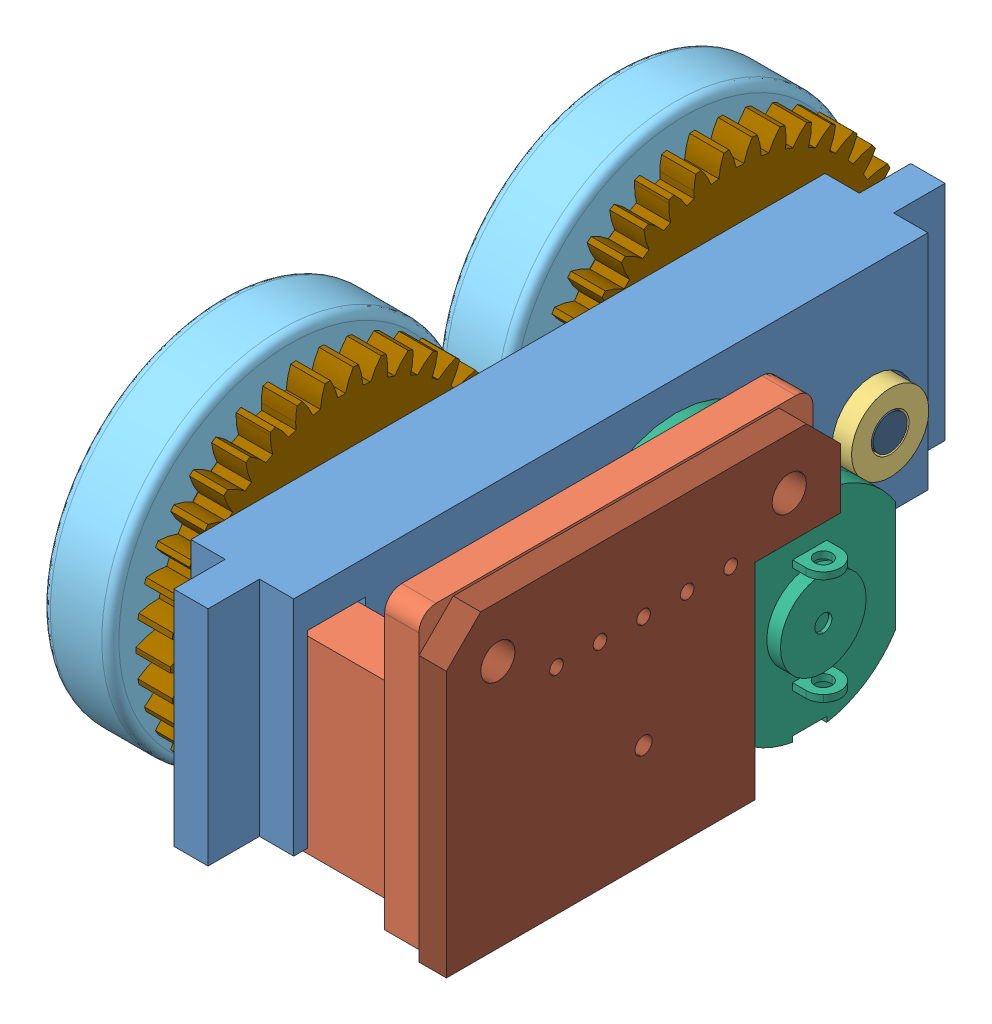
SolidWorks assembly Assem1, configuration Default. Lengths in mm.
Overall size (26.61 22.13 47.3).
19 component instances, 12 part files, 41 mates.
Components (placement in the parent):
- Cum Banh 1-1: Cum Banh 1 [Default] at (16.5178 20.2239 29.5226) x (0 0 -1) z (1 0 0) size (43 13 7.5)
- Ga encoder 1-1: Ga encoder 1 [Default] at (28.5178 22.8543 41.2226) x (0 0 -1) z (0 -1 0) size (23 12 17)
- Ga nam chamV3-1: Ga nam chamV3 [Default] at (21.0178 20.2239 18.0226) x (1 0 0) z (0 -0.059126 0.998251) size (2.5 4.5 4.5)
- Ga nam chamV3.1-1: Ga nam chamV3.1 [Default] at (20.5178 20.2239 41.0226) x (1 0 0) z (0 -0.620557 0.784161) size (7 7.5 7.5)
- Lop banh xe-1: Lop banh xe [Default] at (6.5178 20.2239 41.0226) size (4 21 21)
- N20 DC MOTOR Truc dai-1: N20 DC MOTOR Truc dai [Default] at (30.3178 20.1445 29.5225) x (0 1 0) z (0 0 1) size (12.48 22.6 10.65)
- Nam cham-1: Nam cham [Default] at (26.5178 20.2239 41.0226) x (0 -0.952578 -0.304296) z (1 0 0) size (4 4 2)
- Part4-1: Part4 [Default] at (12.5178 20.2239 41.0226) x (-1 0 0) z (0 0 -1) size (7 15 15)
- Spur gear 0.5M 38T-1: Spur gear 0.5M 38T [Default] at (12.5178 20.2239 41.0226) size (5 19.95 20)
- Truc 2x20-1: Truc 2x20 [Default] at (14.5178 20.2239 41.0226) x (0 0 -1) z (1 0 0) size (2 2 18)
- MT6701 Ver2-1: MT6701 Ver2 [Default] at (32.1278 20.2239 41.0226) x (0 0 -1) z (-1 0 0) size (23 17.5 3.61)
- Part4-2: Part4 [Default] at (12.5178 20.2239 18.0226) x (-1 0 0) z (0 0 -1) size (7 15 15)
- Truc 2x20-2: Truc 2x20 [Default] at (14.5178 20.2239 18.0226) x (0 0.989004 -0.147887) z (1 0 0) size (2 2 18)
- Lop banh xe-2: Lop banh xe [Default] at (6.5178 20.2239 18.0226) size (4 21 21)
- Spur gear 0.5M 38T-2: Spur gear 0.5M 38T [Default] at (12.5178 20.2239 18.0226) x (1 0 0) z (0 0.027407 0.999624) size (5 19.95 20)
- Vong bi 2x5x2.5-2: Vong bi 2x5x2.5 [Default] at (18.627 20.2239 41.0226) x (0 0 -1) z (1 0 0) size (5 5 3)
- Vong bi 2x5x2.5-3: Vong bi 2x5x2.5 [Default] at (21.627 20.2239 41.0226) x (0 0 -1) z (1 0 0) size (5 5 3)
- Vong bi 2x5x2.5-4: Vong bi 2x5x2.5 [Default] at (18.627 20.2239 18.0226) x (0 0 -1) z (1 0 0) size (5 5 3)
- Vong bi 2x5x2.5-6: Vong bi 2x5x2.5 [Default] at (21.627 20.2239 18.0226) x (0 0 -1) z (1 0 0) size (5 5 3)
Mates (geometry in assembly coordinates):
- Concentric1: concentric aligned: cylinder of Cum Banh 1-1 through (22.5178 20.2239 41.0226) axis (-1 0 0) radius 2.6; cylinder of Truc 2x20-1 through (22.3546 20.2239 41.0226) axis (-1 0 0) radius 1
- Concentric2: concentric aligned: cylinder of Cum Banh 1-1 through (22.5178 20.2239 41.0226) axis (-1 0 0) radius 2.6; cylinder of Lop banh xe-1 through (5.3546 20.2239 41.0226) axis (-1 0 0) radius 5.5
- Concentric3: concentric anti-aligned: cylinder of Cum Banh 1-1 through (22.5178 20.2239 41.0226) axis (-1 0 0) radius 2.6; cylinder of Part4-1 through (11.3546 20.2239 41.0226) axis (1 0 0) radius 5.1
- Concentric4: concentric anti-aligned: cylinder of Cum Banh 1-1 through (22.5178 20.2239 41.0226) axis (-1 0 0) radius 2.6; cylinder of Spur gear 0.5M 38T-1 through (8.3546 20.2239 41.0226) axis (1 0 0) radius 2.5
- Concentric5: concentric anti-aligned: cylinder of Cum Banh 1-1 through (22.5178 20.2239 41.0226) axis (-1 0 0) radius 2.6; cylinder of Vong bi 2x5x2.5-2 through (18.627 20.2239 41.0226) axis (1 0 0) radius 2.5
- Concentric6: concentric anti-aligned: cylinder of Cum Banh 1-1 through (22.5178 20.2239 41.0226) axis (-1 0 0) radius 2.6; cylinder of Vong bi 2x5x2.5-3 through (21.627 20.2239 41.0226) axis (1 0 0) radius 2.5
- Concentric7: concentric aligned: cylinder of Cum Banh 1-1 through (22.5178 20.2239 41.0226) axis (-1 0 0) radius 2.6; cylinder of Ga nam chamV3.1-1 through (19.3546 20.2239 41.0226) axis (-1 0 0) radius 3.75
- Concentric8: concentric aligned: cylinder of Cum Banh 1-1 through (22.5178 20.2239 41.0226) axis (-1 0 0) radius 2.6; cylinder of Nam cham-1 through (26.3546 20.2239 41.0226) axis (-1 0 0) radius 2
- Concentric9: concentric aligned: cylinder of Cum Banh 1-1 through (22.5178 20.2239 41.0226) axis (-1 0 0) radius 2.6; cylinder of MT6701 Ver2-1 through (32.3546 20.2239 41.0226) axis (-1 0 0) radius 0.5
- Concentric10: concentric aligned: cylinder of Cum Banh 1-1 through (22.5178 20.2239 18.0226) axis (-1 0 0) radius 2.6; cylinder of Ga nam chamV3-1 through (20.834 20.2239 18.0226) axis (-1 0 0) radius 2.25
- Concentric11: concentric anti-aligned: cylinder of Cum Banh 1-1 through (22.5178 20.2239 18.0226) axis (-1 0 0) radius 2.6; cylinder of Spur gear 0.5M 38T-2 through (8.3546 20.2239 18.0226) axis (1 0 0) radius 2.5
- Concentric12: concentric anti-aligned: cylinder of Cum Banh 1-1 through (22.5178 20.2239 18.0226) axis (-1 0 0) radius 2.6; cylinder of Part4-2 through (11.3546 20.2239 18.0226) axis (1 0 0) radius 5.1
- Concentric13: concentric aligned: cylinder of Cum Banh 1-1 through (22.5178 20.2239 18.0226) axis (-1 0 0) radius 2.6; cylinder of Lop banh xe-2 through (5.3546 20.2239 18.0226) axis (-1 0 0) radius 5.5
- Concentric14: concentric aligned: cylinder of Cum Banh 1-1 through (22.5178 20.2239 18.0226) axis (-1 0 0) radius 2.6; cylinder of Truc 2x20-2 through (23.5178 20.2239 18.0226) axis (-1 0 0) radius 1
- Concentric15: concentric aligned: cylinder of MT6701 Ver2-1 through (34.4646 28.7239 49.5226) axis (-1 0 0) radius 1; cylinder of Ga encoder 1-1 through (29.3546 28.7239 49.5226) axis (-1 0 0) radius 1
- Coincident1: coincident anti-aligned: plane of Part4-1 through (10.3546 20.2239 48.5226) normal (-1 0 0); plane of Lop banh xe-1 through (10.3546 30.7239 41.0226) normal (1 0 0)
- Coincident2: coincident anti-aligned: plane of Part4-1 through (11.3546 20.2239 43.5226) normal (1 0 0); plane of Spur gear 0.5M 38T-1 through (11.3546 20.2239 41.0226) normal (-1 0 0)
- Coincident3: coincident anti-aligned: plane of Spur gear 0.5M 38T-2 through (11.3546 20.2239 18.0226) normal (-1 0 0); plane of Part4-2 through (11.3546 20.2239 20.5226) normal (1 0 0)
- Coincident4: coincident anti-aligned: plane of Lop banh xe-2 through (10.3546 30.7239 18.0226) normal (1 0 0); plane of Part4-2 through (10.3546 20.2239 25.5226) normal (-1 0 0)
- Coincident5: coincident anti-aligned: plane of Vong bi 2x5x2.5-3 through (17.5178 22.7239 41.0226) normal (-1 0 0); plane of Vong bi 2x5x2.5-2 through (17.5178 22.2239 41.0226) normal (1 0 0)
- Coincident6: coincident anti-aligned: plane of Vong bi 2x5x2.5-4 through (17.5178 22.2239 18.0226) normal (1 0 0); plane of Vong bi 2x5x2.5-6 through (17.5178 22.7239 18.0226) normal (-1 0 0)
- Coincident7: coincident aligned: plane of Truc 2x20-1 through (4.3546 20.2239 41.0226) normal (-1 0 0); plane of Part4-1 through (4.3546 20.2239 42.1226) normal (-1 0 0)
- Coincident8: coincident aligned: plane of Truc 2x20-1 through (4.3546 20.2239 41.0226) normal (-1 0 0); plane of Truc 2x20-2 through (5.5178 20.2239 18.0226) normal (-1 0 0)
- Coincident9: coincident aligned: plane of Truc 2x20-1 through (4.3546 20.2239 41.0226) normal (-1 0 0); plane of Part4-2 through (4.3546 20.2239 19.1226) normal (-1 0 0)
- Coincident10: coincident anti-aligned: plane of Cum Banh 1-1 through (20.5178 20.2239 41.0226) normal (-1 0 0); plane of Vong bi 2x5x2.5-3 through (20.5178 22.2239 41.0226) normal (1 0 0)
- Coincident11: coincident anti-aligned: plane of Cum Banh 1-1 through (20.5178 20.2239 18.0226) normal (-1 0 0); plane of Vong bi 2x5x2.5-6 through (20.5178 22.2239 18.0226) normal (1 0 0)
- Concentric16: concentric anti-aligned: cylinder of N20 DC MOTOR Truc dai-1 through (14.2546 20.2239 29.5226) axis (1 0 0) radius 5.9205; cylinder of Cum Banh 1-1 through (22.5178 20.2239 29.5226) axis (-1 0 0) radius 6.25
- Parallel1: parallel aligned: plane of N20 DC MOTOR Truc dai-1 through (14.2546 16.8945 24.5225) normal (0 0 -1); plane of Cum Banh 1-1 through (22.5178 20.2239 34.6226) normal (0 0 -1)
- Concentric17: concentric aligned: cylinder of Vong bi 2x5x2.5-4 through (18.627 20.2239 18.0226) axis (1 0 0) radius 2.5; cylinder of Vong bi 2x5x2.5-6 through (21.627 20.2239 18.0226) axis (1 0 0) radius 2.5
- Concentric18: concentric anti-aligned: cylinder of Vong bi 2x5x2.5-4 through (18.627 20.2239 18.0226) axis (1 0 0) radius 2.5; cylinder of Cum Banh 1-1 through (22.5178 20.2239 18.0226) axis (-1 0 0) radius 2.6
- Coincident13: coincident anti-aligned: plane of Ga nam chamV3.1-1 through (24.3546 21.8706 42.3258) normal (1 0 0); plane of Nam cham-1 through (24.3546 20.2239 41.0226) normal (-1 0 0)
- Coincident14: coincident anti-aligned: plane of Truc 2x20-1 through (22.3546 20.2239 41.0226) normal (1 0 0); plane of Ga nam chamV3.1-1 through (22.3546 20.2239 41.0226) normal (-1 0 0)
- Coincident15: coincident anti-aligned: plane of Spur gear 0.5M 38T-2 through (13.3546 20.2239 18.0226) normal (1 0 0); plane of N20 DC MOTOR Truc dai-1 through (13.3546 20.1176 29.5147) normal (-1 0 0)
- Parallel2: parallel anti-aligned: plane of Ga encoder 1-1 through (17.3546 25.8543 47.8226) normal (-1 0 0); plane of Cum Banh 1-1 through (18.3778 26.2239 29.5226) normal (1 0 0)
- Coincident18: coincident anti-aligned: plane of Ga encoder 1-1 through (29.3546 22.8543 31.6226) normal (1 0 0); plane of MT6701 Ver2-1 through (29.3546 20.2239 41.0226) normal (-1 0 0)
- Concentric19: concentric aligned: cylinder of Ga encoder 1-1 through (29.3546 28.7239 32.5226) axis (-1 0 0) radius 1; cylinder of MT6701 Ver2-1 through (34.4646 28.7239 32.5226) axis (-1 0 0) radius 1
- Distance1: distance = 1 mm anti-aligned: plane of Nam cham-1 through (27.5178 20.2239 41.0226) normal (1 0 0); plane of MT6701 Ver2-1 through (28.5178 20.2239 41.0226) normal (-1 0 0)
- Parallel5: parallel aligned: plane of Cum Banh 1-1 through (22.5178 15.2239 29.5226) normal (0 -1 0); plane of Ga encoder 1-1 through (29.3546 14.8543 47.8226) normal (0 -1 0)
- Parallel6: parallel anti-aligned: plane of Cum Banh 1-1 through (13.0392 26.2239 39.0012) normal (-0.707107 0 0.707107); plane of Ga encoder 1-1 through (24.9546 25.8543 52.2226) normal (0.707107 0 -0.707107)
- Coincident23: coincident anti-aligned: plane of Spur gear 0.5M 38T-2 through (14.5178 20.2239 18.0226) normal (1 0 0); plane of Vong bi 2x5x2.5-4 through (14.5178 22.7239 18.0226) normal (-1 0 0)
- Coincident24: coincident aligned: plane of Ga nam chamV3-1 through (23.5178 21.322 18.0877) normal (1 0 0); plane of Truc 2x20-2 through (23.5178 20.2239 18.0226) normal (1 0 0)
